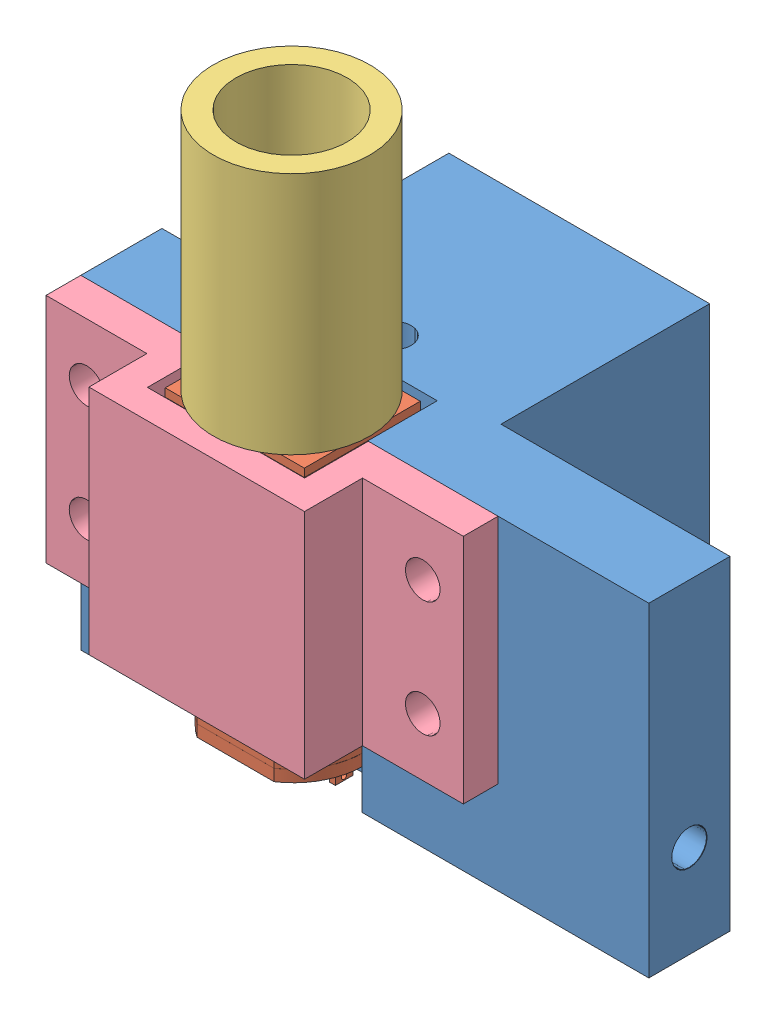
SolidWorks assembly motor_in_mount, configuration Default. Lengths in mm.
Overall size (49 49 33.87).
4 component instances, 4 part files, 7 mates.
Components (placement in the parent):
- back_connector_with motor_slot-1: back_connector_with motor_slot [Default] at (-60.2726 7.3796 -12.4281) size (49 28 25)
- MicroGearmotor v3.step-1: MicroGearmotor v3.step [Default] at (-59.0482 25.3796 4.729) size (12.12 36.12 10.08)
- stick_motor_connector-1: stick_motor_connector [Default] at (-53.0637 35.3796 -0.185) x (-0.536765 0 -0.843732) z (0.843732 0 -0.536765) size (13.5 21 13.5)
- motor_clamp-1: motor_clamp [Default] at (-42.3278 15.3796 3.2623) x (-1 0 0) z (0 0 -1) size (36 20 8)
Mates (geometry in assembly coordinates):
- Coincident2: coincident anti-aligned: plane of back_connector_with motor_slot-1 through (-59.0482 10.3796 -5.2377) normal (0 0 1); plane of MicroGearmotor v3.step-1 through (-56.2733 25.3796 -5.2377) normal (0 0 -1)
- Coincident3: coincident anti-aligned: plane of back_connector_with motor_slot-1 through (-59.0482 10.3796 0.2623) normal (1 0 0); plane of MicroGearmotor v3.step-1 through (-59.0482 34.3796 -5.271) normal (-1 0 0)
- Coincident5: coincident anti-aligned: plane of MicroGearmotor v3.step-1 through (-53.0637 44.3796 0.065) normal (0 1 0); circle of stick_motor_connector-1
- Parallel1: parallel anti-aligned: plane of back_connector_with motor_slot-1 through (-70.7982 35.3796 -24.7377) normal (-1 0 0); plane of motor_clamp-1 through (-34.7982 35.3796 3.2623) normal (1 0 0)
- Coincident12: coincident aligned: circle of back_connector_with motor_slot-1; circle of motor_clamp-1
- Concentric4: concentric anti-aligned: cylinder of MicroGearmotor v3.step-1 through (-53.0637 34.3796 -0.185) axis (0 1 0) radius 1.5; cylinder of stick_motor_connector-1 through (-53.0637 44.3796 -0.185) axis (0 -1 0) radius 1.7
- Coincident16: coincident anti-aligned: plane of back_connector_with motor_slot-1 through (-60.2726 10.3796 -12.4281) normal (0 1 0); plane of MicroGearmotor v3.step-1 through (-52.9496 10.3796 -0.2367) normal (0 -1 0)
